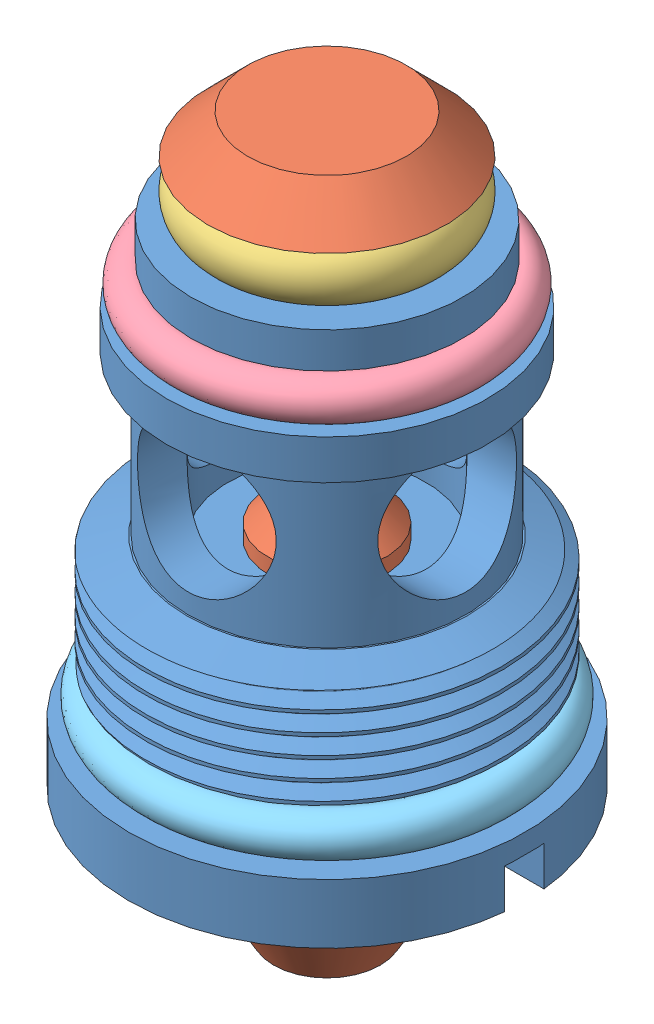
SolidWorks assembly Auslassventil, configuration Standard. Lengths in mm.
Overall size (11.07 18 11.07).
6 component instances, 6 part files, 8 mates.
Components (placement in the parent):
- Auslassventil_Body-1: Auslassventil_Body [Standard] at (-2.9022 -6.2079 0) size (10.39 12.4 10)
- Auslassventil_Stift-1: Auslassventil_Stift [Standard] at (-2.9022 -9.4393 0) x (0.560057 0 -0.828454) z (0.828454 0 0.560057) size (6 18 6)
- ORing1-1: ORing1 [Standard] at (-2.9022 6.8107 0) x (0.890246 0 -0.45548) z (0.45548 0 0.890246) size (6 1.5 6)
- ORing2-1: ORing2 [Standard] at (-2.9022 4.7921 0) x (0.836929 0 0.547312) z (-0.547312 0 0.836929) size (8 1 8)
- Oring3-1: Oring3 [Standard] at (-2.9022 -4.2079 0) size (9.5 1 9.5)
- Feder-1: Feder [Standard] at (-2.9022 -6.7027 0) x (0.967474 0 -0.252969) z (0.252969 0 0.967474) size (4.91 2.75 4.25)
Mates (geometry in assembly coordinates):
- Konzentrisch1: concentric anti-aligned: cylinder of Auslassventil_Body-1 through (-2.9022 10.7921 0) axis (0 -1 0) radius 1.5; cylinder of Auslassventil_Stift-1 through (-2.9022 -6.9393 0) axis (0 1 0) radius 1.5
- Deckungsgleich4: coincident anti-aligned: line of Auslassventil_Stift-1 through (-2.9022 9.4607 0) axis (0 -1 0); line of ORing1-1 through (-2.9022 5.9857 0) axis (0 1 0)
- Tangential14: tangent: plane of Auslassventil_Stift-1 through (-2.9022 6.0607 0) normal (0 1 0); torus of ORing1-1
- Deckungsgleich5: coincident aligned: line of Auslassventil_Body-1 through (-2.9022 6.8121 0) axis (0 -1 0); line of ORing2-1 through (-2.9022 5.3421 0) axis (0 -1 0)
- Tangential15: tangent: plane of Auslassventil_Body-1 through (-2.9022 4.2921 0) normal (0 1 0); torus of ORing2-1
- Deckungsgleich6: coincident aligned: line of Auslassventil_Body-1 through (-2.9022 6.8121 0) axis (0 -1 0); line of Oring3-1 through (-2.9022 -3.6579 0) axis (0 -1 0)
- Tangential16: tangent: plane of Auslassventil_Body-1 through (-2.9022 -4.7079 0) normal (0 1 0); torus of Oring3-1
- Deckungsgleich7: coincident anti-aligned: line of Auslassventil_Stift-1 through (-2.9022 9.4607 0) axis (0 -1 0); line of Feder-1 through (-2.9022 -7.0902 0) axis (0 1 0)
